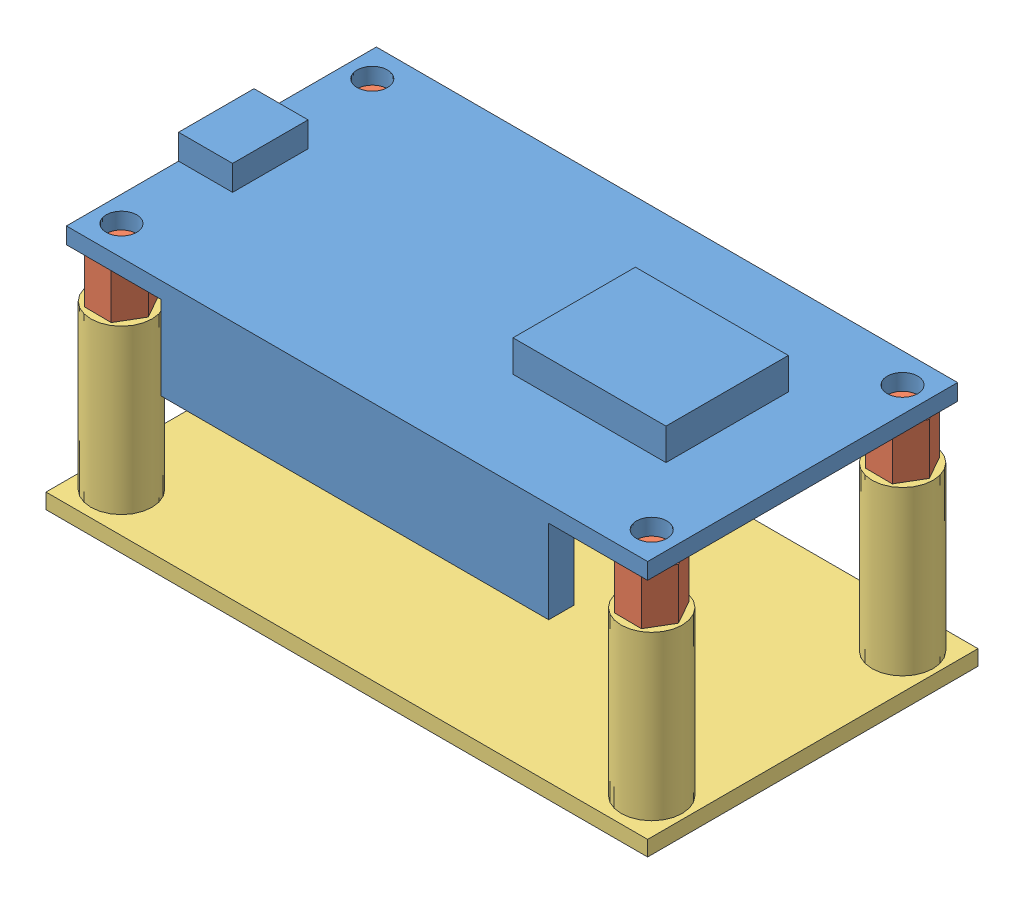
SolidWorks assembly 装配体2, configuration 默认. Lengths in mm.
Overall size (59 27.2 32.4).
6 component instances, 3 part files, 8 mates.
Components (placement in the parent):
- esp8266New-1: esp8266New [默认] at origin size (57 12.9 30.4)
- CopperPillar-2: CopperPillar [默认] at (-16.9001 -5 -10.252) x (1 0 0) z (0 1 0) size (5.31 4.63 8)
- CopperPillar-3: CopperPillar [默认] at (-16.9001 -5 14.348) x (1 0 0) z (0 1 0) size (5.31 4.63 8)
- CopperPillar-4: CopperPillar [默认] at (35.0999 -5 14.348) x (1 0 0) z (0 1 0) size (5.31 4.63 8)
- CopperPillar-5: CopperPillar [默认] at (35.0999 -5 -10.252) x (1 0 0) z (0 1 0) size (5.31 4.63 8)
- 壳-2: 壳 [默认] at (5.238 -22.5 -2.4863) size (59 17.5 32.4)
Mates (geometry in assembly coordinates):
- 重合1: coincident anti-aligned: plane of esp8266New-1 through (0 0 0) normal (0 -1 0); plane of CopperPillar-2 through (-16.9001 0 -10.252) normal (0 1 0)
- 重合2: coincident anti-aligned: plane of esp8266New-1 through (0 0 0) normal (0 -1 0); plane of CopperPillar-5 through (35.0999 0 -10.252) normal (0 1 0)
- 重合3: coincident anti-aligned: plane of esp8266New-1 through (0 0 0) normal (0 -1 0); plane of CopperPillar-3 through (-16.9001 0 14.348) normal (0 1 0)
- 重合4: coincident anti-aligned: plane of esp8266New-1 through (0 0 0) normal (0 -1 0); plane of CopperPillar-4 through (35.0999 0 14.348) normal (0 1 0)
- 同心1: concentric anti-aligned: circle of esp8266New-1; circle of CopperPillar-2
- 同心3: concentric anti-aligned: circle of esp8266New-1; circle of CopperPillar-5
- 同心4: concentric anti-aligned: circle of esp8266New-1; circle of CopperPillar-4
- 距离1: distance = 21 mm anti-aligned: plane of 壳-2 through (5.238 -21 -2.4863) normal (0 1 0); plane of esp8266New-1 through (0 0 0) normal (0 -1 0)
